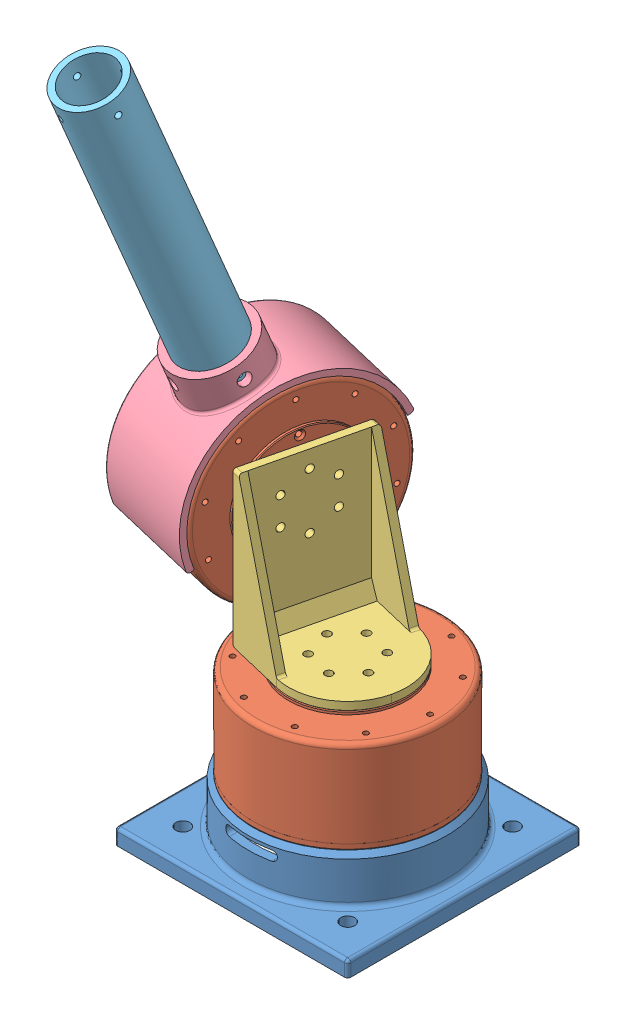
SolidWorks assembly Assembly, configuration Default. Lengths in mm.
Overall size (198.82 426.08 204.44).
6 component instances, 5 part files, 12 mates.
Components (placement in the parent):
- base_link_X10-1: base_link_X10 [По умолчанию] at (81.3757 88.1097 90.3224) size (150 40 150)
- RMD-X10-S2-V3-1: RMD-X10-S2-V3 [По умолчанию] at (81.3757 180.7097 90.3224) x (0 0 -1) z (0 -1 0) size (122 122 74)
- corner_X10-2: corner_X10 [По умолчанию] at (109.5108 189.6097 136.109) x (-0.972655 0 -0.232256) z (0.232256 0 -0.972655) size (76 99 76)
- RMD-X10-S2-V3-2: RMD-X10-S2-V3 [По умолчанию] at (35.7582 259.6097 79.4296) x (-0.23194 -0.052132 0.971332) z (-0.972655 0 -0.232256) size (122 122 74)
- corner_back_muft_X10-1: corner_back_muft_X10 [По умолчанию] at (-20.2667 259.6097 66.0517) x (0.216847 0.358177 -0.908123) z (0.083189 -0.933654 -0.348382) size (129.94 64 146)
- tube-1: tube [По умолчанию] at (7.3963 320.2972 96.5933) x (-0.083189 0.933654 0.348382) z (0.972655 0 0.232256) size (200 40 45)
Mates (geometry in assembly coordinates):
- Концентричный1: concentric anti-aligned: circle of First link-1; circle of RMD-X10-S2-V3-1
- Концентричный2: concentric anti-aligned: circle of First link-1; circle of RMD-X10-S2-V3-1
- Совпадение1: coincident anti-aligned: plane of First link-1 through (81.3757 128.1097 90.3224) normal (0 1 0); plane of RMD-X10-S2-V3-1 through (141.3757 128.1097 90.3224) normal (0 -1 0)
- Концентричный9: concentric anti-aligned: cylinder of RMD-X10-S2-V3-2 through (-15.3453 206.6818 64.3862) axis (-0.972655 0 -0.232256) radius 1.65; circle of corner_back-1
- Концентричный10: concentric anti-aligned: cylinder of RMD-X10-S2-V3-2 through (-8.2424 218.4142 34.6399) axis (-0.972655 0 -0.232256) radius 1.65; circle of corner_back-1
- Совпадение4: coincident anti-aligned: plane of RMD-X10-S2-V3-2 through (-16.1299 319.5282 70.2553) normal (-0.972655 0 -0.232256); plane of corner_back-1 through (-15.4035 259.6097 67.213) normal (0.972655 0 0.232256)
- Концентричный11: concentric aligned: circle of RMD-X10-S2-V3-1; circle of corner-1
- Совпадение5: coincident anti-aligned: plane of RMD-X10-S2-V3-1 through (81.3757 189.6097 90.3224) normal (0 1 0); plane of corner-1 through (53.2405 189.6097 44.5358) normal (0 -1 0)
- Концентричный12: concentric anti-aligned: circle of corner-1; circle of RMD-X10-S2-V3-2
- Совпадение6: coincident anti-aligned: plane of corner-1 through (53.2405 189.6097 44.5358) normal (-0.972655 0 -0.232256); plane of RMD-X10-S2-V3-2 through (44.4148 259.6097 81.4967) normal (0.972655 0 0.232256)
- Совпадение11: coincident: circle of corner_back-1; circle of tube-1
- Концентричный16: concentric anti-aligned: cylinder of corner_back-1 through (17.8781 202.6559 52.6967) axis (-0.083189 0.933654 0.348382) radius 25; cylinder of tube-1 through (-9.2415 507.028 166.2698) axis (0.083189 -0.933654 -0.348382) radius 16
